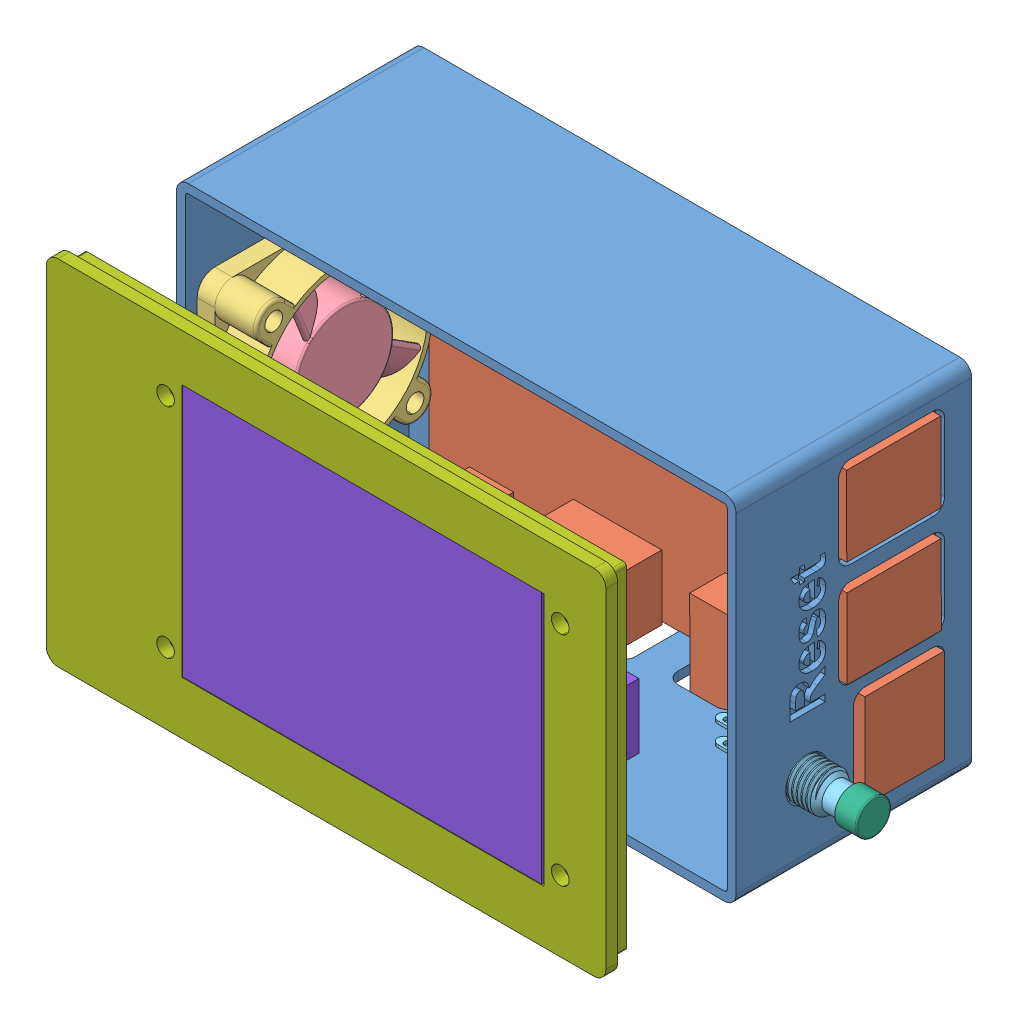
SolidWorks assembly Pi_Case, configuration Default. Lengths in mm.
Overall size (106.4 61.19 62.1).
10 component instances, 8 part files, 13 mates.
Components (placement in the parent):
- Case_btm-1: Case_btm [Default] at (-56.9817 15.7551 73.956) size (95 60 40)
- Raspberry Pi-1: Raspberry Pi [Défaut] at (-77.2486 -159.768 77.556) x (0.999996 0.002984 0) z (0 0 1) size (90.5 58.5 19)
- Fan Assem-1: Fan Assem [Default] at (-73.0593 30.7325 109.822) x (0 0 -1) z (1 0 0) size (39.4 39.4 10.26)
  - Fan Mount-1: Fan Mount [Default] at (12.866 15.0226 17.5776) size (30 30 10.03)
  - Fan Blades-1: Fan Blades [Default] at (12.866 15.0226 23.5776) x (0.770588 0.637333 0) z (0 0 1) size (27.97 28 8.82)
- Button Push Body Assembly-1: Button Push Body Assembly [Predeterminado] at (11.5183 30.3715 101.1619) x (0 1 0) z (1 0 0) size (9.4 9.4 26.5)
  - Button Push Body-1: Button Push Body [Predeterminado] at (-1.6164 0.794 37.9) size (9.4 9.4 22.8)
  - Button Push Body Cap-1: Button Push Body Cap [Predeterminado] at (-1.6164 0.794 37.9) x (0.564495 -0.825437 0) z (0 0 1) size (5.9 5.9 3.7)
- Case_lid-1: Case_lid [Default] at (38.0183 75.7551 134.0608) x (-1 0 0) z (0 0 1) size (95 60 5)
- ili9341 2.4 display-2: ili9341 2.4 display [Default] at (33.0183 67.7551 132.4608) x (-1 0 0) z (0 0 1) size (77.32 43 11.5)
Mates (geometry in assembly coordinates):
- Distance1: distance = 1 mm anti-aligned: plane of Raspberry Pi-1 through (-77.2486 -159.768 76.956) normal (0 0 -1); plane of Case_btm-1 through (36.0183 73.7551 75.956) normal (0 0 1)
- Concentric5: concentric aligned: circle of Case_btm-1; circle of Raspberry Pi-1
- Concentric8: concentric aligned: circle of Case_btm-1; circle of Raspberry Pi-1
- Coincident11: coincident anti-aligned: plane of Case_btm-1 through (36.5183 17.7551 75.956) normal (-1 0 0); plane of Button Push Body Assembly-1/Button Push Body-1 through (36.5183 28.7551 101.956) normal (1 0 0)
- Concentric9: concentric aligned: circle of Case_btm-1; circle of Button Push Body Assembly-1/Button Push Body-1
- Coincident13: coincident anti-aligned: plane of Case_btm-1 through (-55.4817 73.7551 75.956) normal (1 0 0); plane of Fan Assem-1/Fan Mount-1 through (-55.4817 45.7551 96.956) normal (-1 0 0)
- Concentric10: concentric anti-aligned: circle of Case_btm-1; circle of Fan Assem-1/Fan Mount-1
- Concentric11: concentric anti-aligned: circle of Case_btm-1; circle of Fan Assem-1/Fan Mount-1
- Coincident15: coincident aligned: plane of Case_btm-1 through (-54.9817 75.7551 113.956) normal (0 1 0); plane of Case_lid-1 through (36.0183 75.7551 136.0608) normal (0 1 0)
- Coincident16: coincident aligned: plane of Case_btm-1 through (38.0183 17.7551 113.956) normal (1 0 0); plane of Case_lid-1 through (38.0183 73.7551 136.0608) normal (1 0 0)
- Coincident17: coincident anti-aligned: plane of Case_lid-1 through (-33.9817 24.7551 136.0608) normal (1 0 0); plane of ili9341 2.4 display-2 through (-33.9817 67.7551 135.9608) normal (-1 0 0)
- Coincident18: coincident anti-aligned: plane of Case_lid-1 through (-54.9817 17.7551 134.0608) normal (0 0 -1); plane of ili9341 2.4 display-2 through (33.0183 67.7551 134.0608) normal (0 0 1)
- Coincident19: coincident anti-aligned: plane of Case_lid-1 through (27.5183 24.7551 136.0608) normal (0 1 0); plane of ili9341 2.4 display-2 through (33.0183 24.7551 134.0608) normal (0 -1 0)
